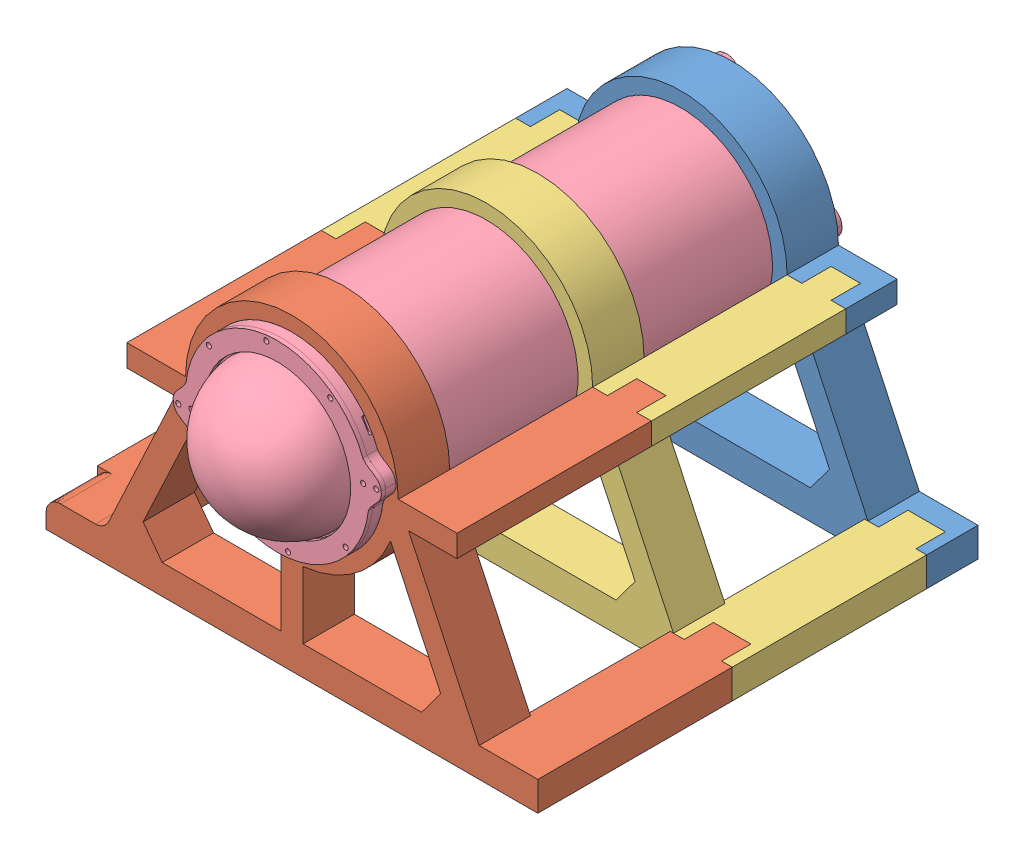
SolidWorks assembly Assem1, configuration Varsayılan. Lengths in mm.
Overall size (335.2 217.7 358.25).
4 component instances, 4 part files, 8 mates.
Components (placement in the parent):
- auv_arka-1: auv_arka [Varsayılan] at (-163.8878 41.3703 317.7018) size (335.2 210.25 35)
- auv_on-1: auv_on [Varsayılan] at (-163.8878 41.3703 582.7018) size (234 172.66 35)
- auv_orta-1: auv_orta [Varsayılan] at (-163.8878 41.3703 450.2018) size (335.2 210.25 152.5)
- auvtup30cm-1: auvtup30cm [Default] at (-150.759 45.5035 331.7018) x (0.992058 0.125779 0) z (0 0 1) size (143.05 134.03 358.25)
Mates (geometry in assembly coordinates):
- Coincident2: coincident: point of assembly; point of assembly; moEndPointRef_w of auv_on-1; moEndPointRef_w of auv_orta-1
- Coincident3: coincident: point of assembly; point of assembly; moEndPointRef_w of auv_on-1; moEndPointRef_w of auv_orta-1
- Coincident4: coincident: point of assembly; point of assembly; moEndPointRef_w of auv_on-1; moEndPointRef_w of auv_orta-1
- Coincident6: coincident: unknown of auv_arka-1; unknown of auv_orta-1
- Coincident7: coincident: unknown of auv_arka-1; unknown of auv_orta-1
- Coincident8: coincident: unknown of auv_arka-1; unknown of auv_orta-1
- Concentric1: concentric aligned: cylinder of auv_arka-1 through (-163.8878 41.3703 352.7018) axis (0 0 -1) radius 62.5; cylinder of auvtup30cm-1 through (-163.8878 41.3703 617.7018) axis (0 0 -1) radius 62.5
- Coincident9: coincident: circle of auv_on-1; circle of auvtup30cm-1
